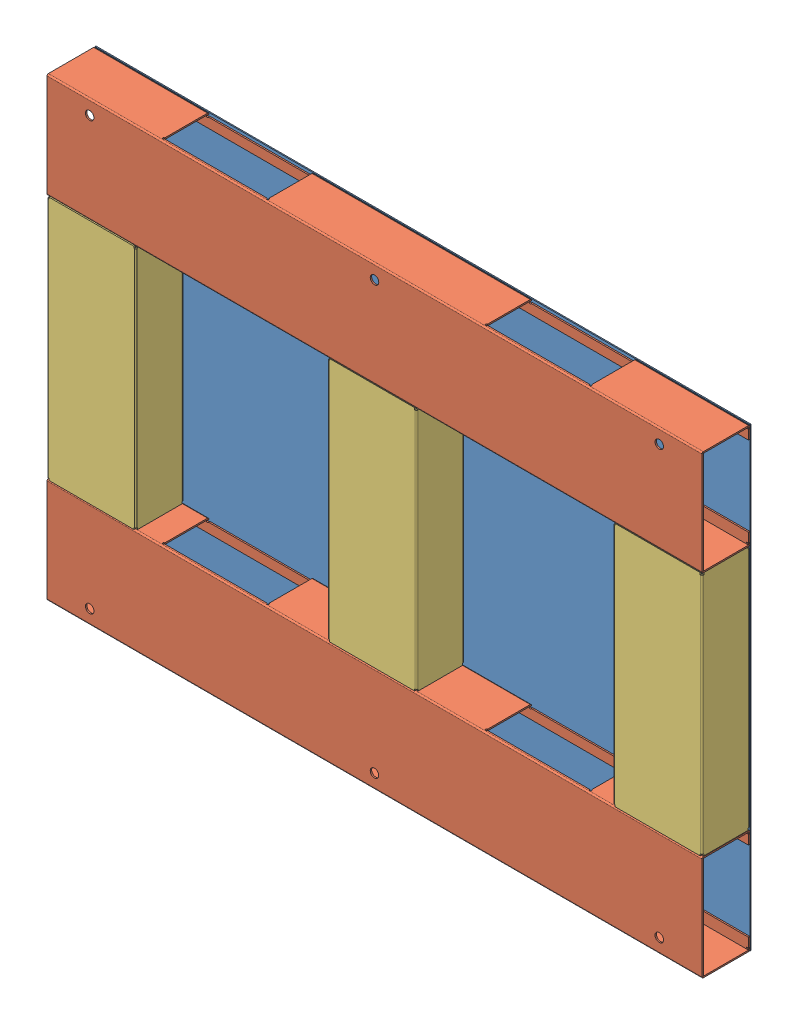
SolidWorks assembly 底板, configuration 預設. Lengths in mm.
Overall size (1380.01 960 103.29).
6 component instances, 3 part files, 15 mates.
Components (placement in the parent):
- LB-A54A-02-26-1: LB-A54A-02-26 [預設] at (-83868.7741 4779.2866 -1.15) size (1380 960 2.3)
- LB-A54-01-1-1: LB-A54-01-1 [預設] at (-4146.7623 -34163.5866 99.142) size (1380 221 100.99)
- LB-A54-01-1-2: LB-A54-01-1 [預設] at (4166.9713 34133.8822 99.142) x (-1 0 0) z (0 0 1) size (1380 221 100.99)
- LB-A54A-02-48-1: LB-A54A-02-48 [預設] at (-5795.5581 81855.4362 102.142) x (0 -1 0) z (0 0 -1) size (517 187 100.99)
- LB-A54A-02-48-2: LB-A54A-02-48 [預設] at (-5204.2988 81856.4362 102.142) x (0 -1 0) z (0 0 -1) size (517 187 100.99)
- LB-A54A-02-48-3: LB-A54A-02-48 [預設] at (-4602.5501 81856.4362 102.142) x (0 -1 0) z (0 0 -1) size (517 187 100.99)
Mates (geometry in assembly coordinates):
- 重合/共線/共點1: coincident anti-aligned: plane of LB-A54A-02-26-1 through (-679.8955 -494.8522 1.15) normal (0 0 1); plane of LB-A54-01-1-1 through (700.1045 438.6558 1.15) normal (0 0 -1)
- 重合/共線/共點2: coincident aligned: plane of LB-A54A-02-26-1 through (700.1045 465.1478 1.15) normal (0 1 0); plane of LB-A54-01-1-1 through (700.1045 465.1478 -19.35) normal (0 1 0)
- 重合/共線/共點3: coincident aligned: plane of LB-A54A-02-26-1 through (-679.8955 465.1478 1.15) normal (-1 0 0); plane of LB-A54-01-1-1 through (-679.8955 438.6558 1.15) normal (-1 0 0)
- 重合/共線/共點4: coincident anti-aligned: plane of LB-A54A-02-26-1 through (-679.8955 -494.8522 1.15) normal (0 0 1); plane of LB-A54-01-1-2 through (-679.8955 151.6558 1.15) normal (0 0 -1)
- 重合/共線/共點5: coincident aligned: plane of LB-A54A-02-26-1 through (-679.8955 -494.8522 1.15) normal (0 -1 0); plane of LB-A54-01-1-2
- 重合/共線/共點6: coincident: line of LB-A54A-02-26-1 through (-679.8955 465.1478 1.15) axis (0 -1 0); plane of LB-A54-01-1-2 through (-679.8955 -468.3602 1.15) normal (-1 0 0)
- 重合/共線/共點7: coincident anti-aligned: plane of LB-A54A-02-26-1 through (-679.8955 -494.8522 1.15) normal (0 0 1); plane of LB-A54A-02-48-1 through (-656.3995 -273.8522 1.15) normal (0 0 -1)
- 重合/共線/共點8: coincident: line of LB-A54A-02-26-1 through (-679.8955 465.1478 1.15) axis (0 -1 0); plane of LB-A54A-02-48-1 through (-679.8955 -273.8522 -16.354) normal (-1 0 0)
- 重合/共線/共點9: coincident anti-aligned: plane of LB-A54-01-1-2 through (-679.8955 -273.8522 432.65) normal (0 1 0); plane of LB-A54A-02-48-1 through (-676.1495 -273.8522 99.142) normal (0 -1 0)
- 重合/共線/共點10: coincident anti-aligned: plane of LB-A54A-02-26-1 through (-679.8955 -494.8522 1.15) normal (0 0 1); plane of LB-A54A-02-48-2 through (-65.1402 -272.8522 1.15) normal (0 0 -1)
- 重合/共線/共點11: coincident anti-aligned: plane of LB-A54-01-1-1; plane of LB-A54A-02-48-2 through (-85.6362 244.1478 4.896) normal (0 1 0)
- 重合/共線/共點12: coincident: line of LB-A54A-02-26-1 through (98.3558 -494.8522 -1.15) axis (0 1 0); plane of LB-A54A-02-48-2 through (98.3558 -272.8522 395.646) normal (1 0 0)
- 重合/共線/共點13: coincident anti-aligned: plane of LB-A54A-02-48-3 through (536.6085 487.2195 1.15) normal (0 0 -1); plane of LB-A54A-02-26-1 through (-679.8955 -494.8522 1.15) normal (0 0 1)
- 重合/共線/共點14: coincident aligned: plane of LB-A54A-02-26-1 through (700.1045 -494.8522 1.15) normal (1 0 0); plane of LB-A54A-02-48-3 through (700.1045 487.2195 395.646) normal (1 0 0)
- 重合/共線/共點15: coincident anti-aligned: plane of LB-A54-01-1-1; plane of LB-A54A-02-48-3 through (516.1125 1004.2195 4.896) normal (0 1 0)
